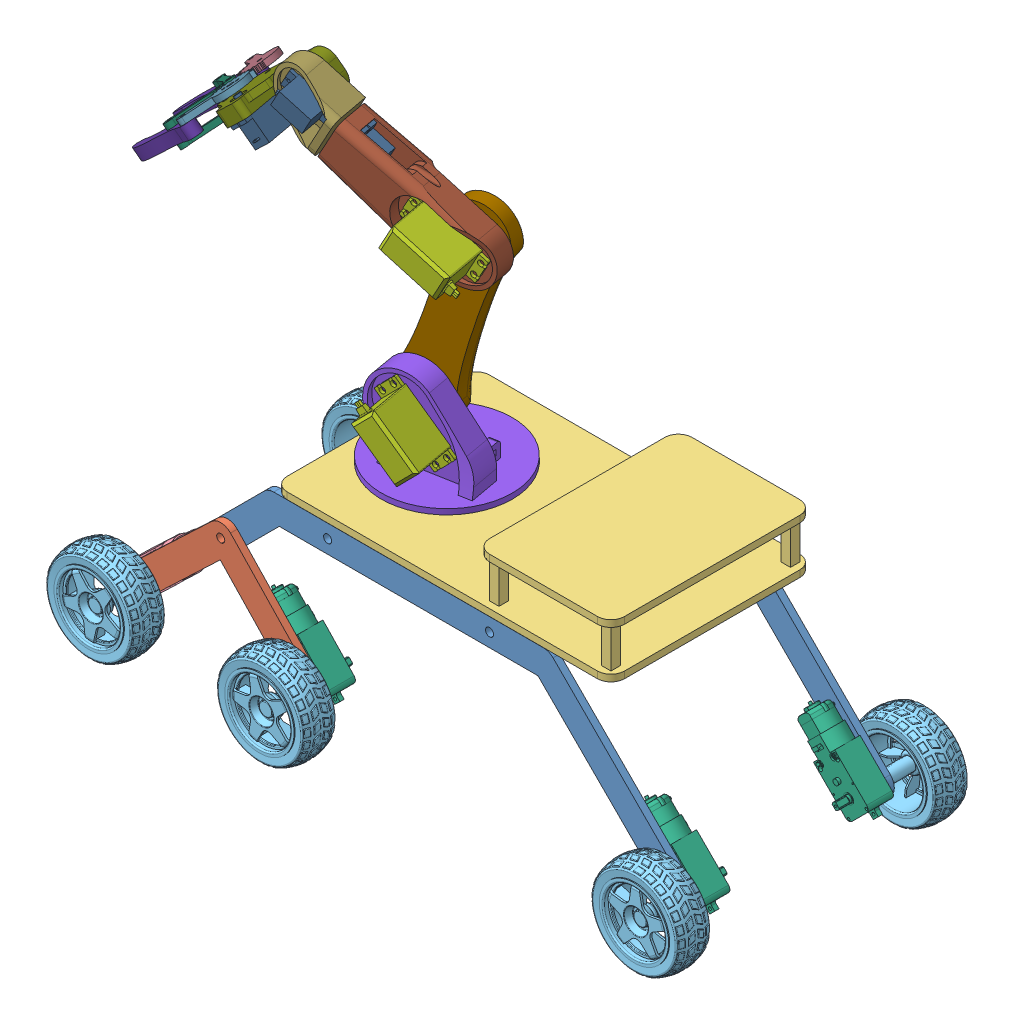
SolidWorks assembly rb ass, configuration Default. Lengths in mm.
Overall size (485.98 395.02 226).
38 component instances, 17 part files, 47 mates.
Components (placement in the parent):
- rb1-1: rb1 [Default] at (193.6018 218.4548 283.5774) size (354.23 120 5)
- rb2-1: rb2 [Default] at (-40.6311 184.2218 288.5774) x (0.998933 -0.046181 0) z (0 0 1) size (146.58 84.61 5)
- rb3-1: rb3 [Default] at (-6.3982 233.5548 138.5774) x (1 0 0) z (0 -1 0) size (250 150 60)
- rb1-2: rb1 [Default] at (193.6018 218.4548 138.5774) size (354.23 120 5)
- rb2-2: rb2 [Default] at (-40.6311 184.2218 133.5774) x (1 0.000061 0) z (0 0 1) size (146.58 84.61 5)
- motoreducteur-1: motoreducteur [Default] at (-79.1029 132.2734 269.7774) x (0.724836 0.688921 0) z (0 0 1) size (70.34 22.5 38.2)
- Wheel D65x25-1: Wheel D65x25 [По умолчанию] at (-105.5214 122.5468 326.5774) x (0.778778 -0.627299 0) z (0 0 1) size (69.23 69.36 30)
- motoreducteur (1)-1: motoreducteur (1) [Default] at (283.2074 144.6177 143.5774) x (-0.707107 0.707107 0) z (0 0 1) size (70.34 22.5 38.2)
- Wheel D65x25-2: Wheel D65x25 [По умолчанию] at (293.6018 118.4548 105.5774) x (0.994105 -0.108423 0) z (0 0 -1) size (69.23 69.36 30)
- motoreducteur (1)-2: motoreducteur (1) [Default] at (283.2074 144.6177 264.7774) x (-0.707107 0.707107 0) z (0 0 1) size (70.34 22.5 38.2)
- motoreducteur (1)-3: motoreducteur (1) [Default] at (11.3144 145.753 269.7774) x (-0.688921 0.724836 0) z (0 0 1) size (70.34 22.5 38.2)
- motoreducteur (1)-4: motoreducteur (1) [Default] at (13.0378 148.1962 138.5774) x (-0.721703 0.692203 0) z (0 0 1) size (70.34 22.5 38.2)
- motoreducteur (1)-5: motoreducteur (1) [Default] at (-76.6595 130.55 138.5774) x (0.692203 0.721703 0) z (0 0 1) size (70.34 22.5 38.2)
- Wheel D65x25-3: Wheel D65x25 [По умолчанию] at (23.9757 122.2558 100.5774) x (0.966066 -0.258297 0) z (0 0 -1) size (69.23 69.36 30)
- Wheel D65x25-4: Wheel D65x25 [По умолчанию] at (-102.6 119.612 100.5774) x (0.996582 0.082612 0) z (0 0 -1) size (69.23 69.36 30)
- Wheel D65x25-5: Wheel D65x25 [По умолчанию] at (293.6018 118.4548 321.5774) x (0.999602 0.028207 0) z (0 0 1) size (69.23 69.36 30)
- Wheel D65x25-6: Wheel D65x25 [По умолчанию] at (21.0411 119.3345 326.5774) x (0.953134 0.30255 0) z (0 0 1) size (69.23 69.36 30)
- Robotic Arm-1: Robotic Arm [Default] at (2.5225 140.4472 117.0612) size (253.4 283.17 139.57)
  - Servo Motor MG996R-1: Servo Motor MG996R [Default] at (30.5293 45.3076 92.8796) x (-1 0 0) z (0 0 -1) size (55.8 47.4 21)
  - Waist-1: Waist [Default] at (40.7793 93.1076 92.8796) x (-0.178802 0 -0.983885) z (0.983885 0 -0.178802) size (97 64.78 97)
  - Servo Motor MG996R-2: Servo Motor MG996R [Default] at (43.1871 126.313 142.4478) x (0.695712 -0.707107 -0.126432) z (0.695712 0.707107 -0.126432) size (55.8 47.4 21)
  - Arm 01-1: Arm 01 [Default] at (27.5808 133.5608 97.1076) x (-0.941109 0.291655 0.171029) z (-0.178802 0 -0.983885) size (54.87 166.68 26.36)
  - Servo Motor Micro  9g-1: Servo Motor Micro  9g [Default] at (9.904 276.4834 111.1953) x (0.448013 0.890312 -0.081418) z (0.178802 0 0.983885) size (32.6 29.9 12.4)
  - Servo Motor MG996R-7: Servo Motor MG996R [Default] at (61.512 253.011 139.1176) x (-0.875965 0.455351 0.15919) z (-0.448013 -0.890312 0.081418) size (55.8 47.4 21)
  - Arm 02 v3-1: Arm 02 v3 [Default] at (32.6174 264.3897 101.4775) x (0.448013 0.890312 -0.081418) z (0.178802 0 0.983885) size (38.57 115 28.32)
  - Arm 03-1: Arm 03 [Default] at (-16.3245 290.0092 116.0058) x (0.449545 0.890278 -0.072895) z (0.174916 -0.00771 0.984553) size (33 46 28)
  - Servo Motor Micro  9g-2: Servo Motor Micro  9g [Default] at (-33.8391 300.3245 133.9765) x (0.875965 -0.455351 -0.15919) z (0.449545 0.890278 -0.072895) size (32.6 29.9 12.4)
  - Gripper Assembly-1: Gripper Assembly [Default] at (-33.1508 318.0568 111.777) x (0.174916 -0.00771 0.984553) z (-0.719312 -0.683812 0.122438) size (98.22 36.05 139.41)
    - gear1-1: gear1 [Default] at (-22.9056 12.6028 63.2843) x (-0.581668 0 0.813426) z (-0.813426 0 -0.581668) size (49.29 4 26.63)
    - gear2-1: gear2 [Default] at (5.149 12.6028 46.1292) x (-0.467421 0 -0.884035) z (0.884035 0 -0.467421) size (49.02 4 26.63)
    - grip link 1-1: grip link 1 [Default] at (-26.7426 0.1028 100.5029) x (0.571471 0 -0.820623) z (0.820623 0 0.571471) size (39 4 8)
    - Gripper base-1: Gripper base [Default] at (-22.027 4.1028 80.0636) size (44.4 28 77)
    - grip link 1-2: grip link 1 [Default] at (18.9346 0.1028 100.3298) x (-0.579406 0 -0.815039) z (0.815039 0 -0.579406) size (39 4 8)
    - Gripper 1-1: Gripper 1 [Default] at (25.0683 4.1028 73.5645) x (0 1 0) z (0.39713 0 -0.917762) size (8.5 22.22 65.31)
    - Gripper 1-2: Gripper 1 [Default] at (-32.1279 12.6028 73.5771) x (0 -1 0) z (-0.371396 0 -0.928475) size (8.5 22.22 65.31)
    - Servo Motor Micro  9g-1: Servo Motor Micro  9g [Default] at (4.773 -19.4472 55.0636) x (-1 0 0) z (0 0 -1) size (32.6 29.9 12.4)
    - grip link 1-3: grip link 1 [Default] at (18.9346 12.6028 100.3298) x (-0.579406 0 -0.815039) z (0.815039 0 -0.579406) size (39 4 8)
    - grip link 1-4: grip link 1 [Default] at (-26.7426 16.6028 100.5029) x (0.571471 0 -0.820623) z (-0.820623 0 -0.571471) size (39 4 8)
Mates (geometry in assembly coordinates):
- Coincident1: coincident anti-aligned: plane of rb1-1 through (193.6018 218.4548 283.5774) normal (0 0 -1); plane of rb3-1 through (43.6018 208.5548 283.5774) normal (0 0 1)
- Concentric1: concentric aligned: cylinder of rb1-1 through (33.6018 218.4548 288.5774) axis (0 0 -1) radius 3; cylinder of rb3-1 through (33.6018 218.4548 288.5774) axis (0 0 -1) radius 3
- Concentric2: concentric aligned: cylinder of rb1-1 through (153.6018 218.4548 288.5774) axis (0 0 -1) radius 3; cylinder of rb3-1 through (153.6018 218.4548 288.5774) axis (0 0 -1) radius 3
- Concentric3: concentric aligned: cylinder of rb1-1 through (-40.6311 184.2218 288.5774) axis (0 0 -1) radius 3; cylinder of rb2-1 through (-40.6311 184.2218 293.5774) axis (0 0 -1) radius 3
- Concentric4: concentric aligned: cylinder of rb3-1 through (153.6018 218.4548 288.5774) axis (0 0 -1) radius 3; cylinder of rb1-2 through (153.6018 218.4548 143.5774) axis (0 0 -1) radius 3
- Coincident2: coincident anti-aligned: plane of rb3-1 through (143.6018 208.5548 143.5774) normal (0 0 -1); plane of rb1-2 through (193.6018 218.4548 143.5774) normal (0 0 1)
- Concentric5: concentric aligned: cylinder of rb3-1 through (33.6018 218.4548 288.5774) axis (0 0 -1) radius 3; cylinder of rb1-2 through (33.6018 218.4548 143.5774) axis (0 0 -1) radius 3
- Concentric6: concentric aligned: cylinder of rb1-2 through (-40.6311 184.2218 143.5774) axis (0 0 -1) radius 3; cylinder of rb2-2 through (-40.6311 184.2218 138.5774) axis (0 0 -1) radius 3
- Coincident3: coincident anti-aligned: plane of rb1-1 through (193.6018 218.4548 288.5774) normal (0 0 1); plane of rb2-1 through (-105.5214 122.5468 288.5774) normal (0 0 -1)
- Coincident4: coincident anti-aligned: plane of rb1-2 through (193.6018 218.4548 138.5774) normal (0 0 -1); plane of rb2-2 through (-102.6 119.612 138.5774) normal (0 0 1)
- Parallel2: parallel anti-aligned: cylinder of rb2-1 through (-105.5214 122.5468 293.5774) axis (0 0 -1) radius 3; cylinder of motoreducteur-1 through (-105.5214 122.5468 290.4274) axis (0 0 1) radius 0.875
- Concentric9: concentric anti-aligned: cylinder of rb2-1 through (-105.5214 122.5468 293.5774) axis (0 0 -1) radius 3; cylinder of motoreducteur-1 through (-105.5214 122.5468 290.4274) axis (0 0 1) radius 0.875
- Parallel3: parallel aligned: line of rb2-1 through (-47.5203 191.4702 288.5774) axis (-0.724836 -0.688921 0); line of motoreducteur-1 through (-94.4659 148.4373 288.5774) axis (-0.724836 -0.688921 0)
- Concentric10: concentric anti-aligned: cylinder of motoreducteur-1 through (-105.5214 122.5468 298.2774) axis (0 0 -1) radius 2.55; cylinder of Wheel D65x25-1 through (-105.5214 122.5468 326.5774) axis (0 0 1) radius 2.75
- Distance1: distance = 3 mm anti-aligned: plane of Wheel D65x25-1 through (-105.5214 122.5468 296.5774) normal (0 0 -1); plane of rb2-1 through (-105.5214 122.5468 293.5774) normal (0 0 1)
- Concentric11: concentric aligned: cylinder of rb2-2 through (-102.6 119.612 138.5774) axis (0 0 -1) radius 3; cylinder of motoreducteur (1)-5 through (-102.6 119.612 137.6274) axis (0 0 -1) radius 0.875
- Coincident8: coincident anti-aligned: plane of rb2-1 through (-105.5214 122.5468 288.5774) normal (0 0 -1); plane of motoreducteur-1 through (-105.7962 111.7315 288.5774) normal (0 0 1)
- Coincident9: coincident anti-aligned: plane of rb2-2 through (-102.6 119.612 138.5774) normal (0 0 1); plane of motoreducteur (1)-5 through (-102.3743 108.7957 138.5774) normal (0 0 -1)
- Parallel5: parallel aligned: line of rb2-2 through (-47.8481 191.1439 138.5774) axis (-0.692203 -0.721703 0); line of motoreducteur (1)-5 through (-92.7535 145.9861 138.5774) axis (-0.692203 -0.721703 0)
- Concentric12: concentric aligned: cylinder of rb2-2 through (23.9757 122.2558 138.5774) axis (0 0 -1) radius 3; cylinder of motoreducteur (1)-4 through (23.9757 122.2558 137.6274) axis (0 0 -1) radius 0.875
- Coincident11: coincident anti-aligned: plane of rb2-2 through (-102.6 119.612 138.5774) normal (0 0 1); plane of motoreducteur (1)-4 through (34.7921 122.4815 138.5774) normal (0 0 -1)
- Parallel8: parallel aligned: line of rb2-2 through (30.8977 129.4728 138.5774) axis (-0.721703 0.692203 0); line of motoreducteur (1)-4 through (37.2148 125.0074 138.5774) axis (-0.721703 0.692203 0)
- Concentric13: concentric anti-aligned: cylinder of rb2-1 through (21.0411 119.3345 293.5774) axis (0 0 -1) radius 3; cylinder of motoreducteur (1)-3 through (21.0411 119.3345 290.4274) axis (0 0 1) radius 0.875
- Coincident14: coincident anti-aligned: plane of rb2-1 through (-105.5214 122.5468 288.5774) normal (0 0 -1); plane of motoreducteur (1)-3 through (31.8564 119.0597 288.5774) normal (0 0 1)
- Parallel9: parallel aligned: line of rb2-1 through (-40.9903 170.0842 288.5774) axis (0.688921 -0.724836 0); line of motoreducteur (1)-3 through (-4.8494 130.39 288.5774) axis (0.688921 -0.724836 0)
- Coincident16: coincident anti-aligned: plane of rb1-1 through (193.6018 218.4548 283.5774) normal (0 0 -1); plane of motoreducteur (1)-2 through (304.4206 118.4548 283.5774) normal (0 0 1)
- Concentric14: concentric anti-aligned: cylinder of rb1-1 through (293.6018 118.4548 288.5774) axis (0 0 -1) radius 3; cylinder of motoreducteur (1)-2 through (293.6018 118.4548 285.4274) axis (0 0 1) radius 0.875
- Parallel10: parallel anti-aligned: line of rb1-1 through (200.6729 225.5258 283.5774) axis (0.707107 -0.707107 0); line of motoreducteur (1)-2 through (306.8955 120.9296 283.5774) axis (-0.707107 0.707107 0)
- Coincident18: coincident anti-aligned: plane of rb1-2 through (193.6018 218.4548 143.5774) normal (0 0 1); plane of motoreducteur (1)-1 through (304.4206 118.4548 143.5774) normal (0 0 -1)
- Concentric15: concentric aligned: cylinder of rb1-2 through (293.6018 118.4548 143.5774) axis (0 0 -1) radius 3; cylinder of motoreducteur (1)-1 through (293.6018 118.4548 142.6274) axis (0 0 -1) radius 0.875
- Parallel11: parallel anti-aligned: line of rb1-2 through (200.6729 225.5258 143.5774) axis (0.707107 -0.707107 0); line of motoreducteur (1)-1 through (306.8955 120.9296 143.5774) axis (-0.707107 0.707107 0)
- Concentric17: concentric aligned: cylinder of motoreducteur (1)-1 through (293.6018 118.4548 172.0774) axis (0 0 -1) radius 2.55; cylinder of Wheel D65x25-2 through (293.6018 118.4548 105.5774) axis (0 0 -1) radius 2.75
- Distance2: distance = 3 mm anti-aligned: plane of Wheel D65x25-2 through (293.6018 118.4548 135.5774) normal (0 0 1); plane of rb1-2 through (193.6018 218.4548 138.5774) normal (0 0 -1)
- Concentric18: concentric anti-aligned: cylinder of motoreducteur (1)-2 through (293.6018 118.4548 293.2774) axis (0 0 -1) radius 2.55; cylinder of Wheel D65x25-5 through (293.6018 118.4548 321.5774) axis (0 0 1) radius 2.75
- Distance3: distance = 3 mm anti-aligned: plane of Wheel D65x25-5 through (293.6018 118.4548 291.5774) normal (0 0 -1); plane of rb1-1 through (193.6018 218.4548 288.5774) normal (0 0 1)
- Concentric19: concentric anti-aligned: cylinder of motoreducteur (1)-3 through (21.0411 119.3345 298.2774) axis (0 0 -1) radius 2.55; cylinder of Wheel D65x25-6 through (21.0411 119.3345 326.5774) axis (0 0 1) radius 2.75
- Distance4: distance = 3 mm anti-aligned: plane of Wheel D65x25-6 through (21.0411 119.3345 296.5774) normal (0 0 -1); plane of rb2-1 through (-105.5214 122.5468 293.5774) normal (0 0 1)
- Concentric20: concentric aligned: cylinder of motoreducteur (1)-5 through (-102.6 119.612 167.0774) axis (0 0 -1) radius 2.55; cylinder of Wheel D65x25-4 through (-102.6 119.612 100.5774) axis (0 0 -1) radius 2.75
- Distance5: distance = 3 mm anti-aligned: plane of Wheel D65x25-4 through (-102.6 119.612 130.5774) normal (0 0 1); plane of rb2-2 through (-102.6 119.612 133.5774) normal (0 0 -1)
- Concentric21: concentric aligned: cylinder of motoreducteur (1)-4 through (23.9757 122.2558 167.0774) axis (0 0 -1) radius 2.55; cylinder of Wheel D65x25-3 through (23.9757 122.2558 100.5774) axis (0 0 -1) radius 2.75
- Distance6: distance = 3 mm anti-aligned: plane of Wheel D65x25-3 through (23.9757 122.2558 130.5774) normal (0 0 1); plane of rb2-2 through (-102.6 119.612 133.5774) normal (0 0 -1)
- Coincident24: coincident anti-aligned: plane of rb3-1 through (-6.3982 233.5548 138.5774) normal (0 1 0); plane of ? through (57.702 233.5548 212.5668) normal (0 -1 0)
- Lock1: lock: unknown of rb3-1; unknown of ?
- Parallel12: parallel aligned: line of rb3-1 through (-6.3982 233.5548 148.5774) axis (0 0 1); line of Robotic Arm-1/Servo Motor MG996R-1 through (12.5517 187.7548 200.4908) axis (0 0 1)
- Coincident28: coincident anti-aligned: plane of rb3-1 through (-6.3982 233.5548 138.5774) normal (0 1 0); plane of Robotic Arm-1/Waist-1 through (43.3017 233.5548 209.9408) normal (0 -1 0)
- Parallel14: parallel aligned: line of rb3-1 through (-6.3982 228.5548 148.5774) axis (0 0 1); line of Robotic Arm-1/Servo Motor MG996R-1 through (12.5517 187.7548 200.4908) axis (0 0 1)
- Distance8: distance = 63.3866 mm anti-aligned: plane of Robotic Arm-1/Servo Motor MG996R-1 through (53.5517 222.7548 220.1908) normal (0 0 1); plane of rb1-1 through (193.6018 218.4548 283.5774) normal (0 0 -1)
